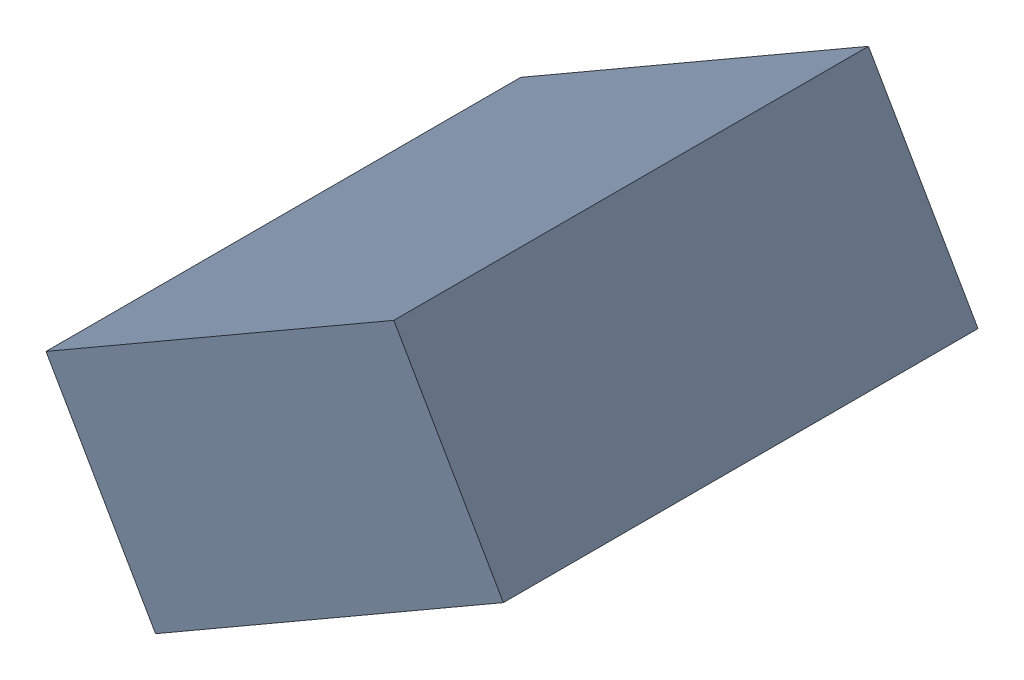
SolidWorks assembly C22_TDA2, configuration Standard. Lengths in mm.
Overall size (1.25 1.07 1.3).
2 component instances, 1 part files, 0 mates.
Components (placement in the parent):
- 885542920-1: 885542920 [Standard] at (42.5637 33.0726 0) size (1.25 1.07 1.3)
  - Extruded_24-1: Extruded_24 [Standard] at origin size (1.25 1.07 1.3)
